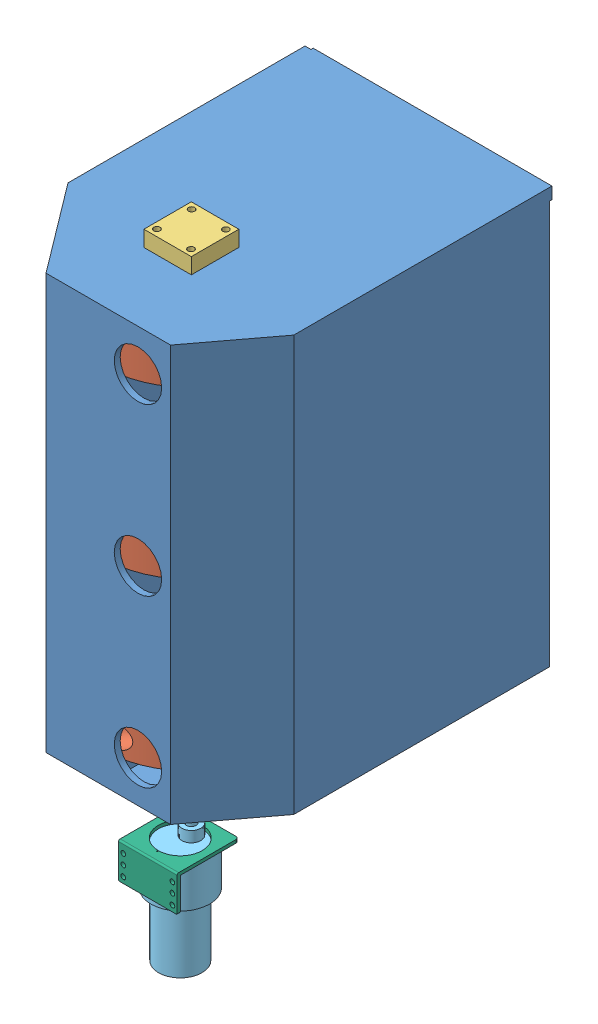
SolidWorks assembly seed drill tank, configuration Default. Lengths in mm.
Overall size (158.83 396.8 236.15).
9 component instances, 7 part files, 22 mates.
Components (placement in the parent):
- container-1: container [Default] at (54.6406 23.9076 482.5633) size (154.72 292.5 217.66)
- divider-1: divider [Default] at (46.3176 108.9519 394.803) x (-0.517121 0 0.855912) z (0.855912 0 0.517121) size (111 22.5 111)
- divider-2: divider [Default] at (46.3176 318.9519 394.803) x (0.703833 0 0.710366) z (0.710366 0 -0.703833) size (111 22.5 111)
- divider-3: divider [Default] at (46.3176 213.9519 394.803) x (0.414054 0 0.910252) z (0.910252 0 -0.414054) size (111 22.5 111)
- ball bearing-1: ball bearing [Default] at (46.3176 340.2019 394.803) x (0 0 -1) z (-1 0 0) size (30 10 30)
- bearing-1: bearing [Default] at (46.3176 67.7019 394.803) x (-1 0 0) z (0 0 1) size (30.31 10 30)
- DC motor-1: DC motor [Default] at (46.3176 8.4019 401.803) x (-1 0 0) z (0 -1 0) size (37 37 101.8)
- DCclamp-1: DCclamp [Default] at (27.8176 8.4019 420.303) x (0 -1 0) z (1 0 0) size (22.5 39 37)
- shaft-1: shaft [Default] at (46.3176 52.2019 394.803) x (0 0 1) z (1 0 0) size (16.38 20 16.38)
Mates (geometry in assembly coordinates):
- Coincident2: coincident: plane of container-1 through (42.5676 315.2019 451.053) normal (0 -1 0); plane of divider-2 through (46.3176 315.2019 394.803) normal (0 1 0)
- Coincident3: coincident: plane of container-1 through (42.5676 187.7019 451.053) normal (0 1 0); plane of divider-3 through (46.3176 187.7019 394.803) normal (0 -1 0)
- Coincident4: coincident: plane of container-1 through (42.5676 105.2019 451.053) normal (0 -1 0); plane of divider-1 through (46.3176 105.2019 394.803) normal (0 1 0)
- Concentric4: concentric: cylinder of container-1 through (46.3176 337.7019 394.803) axis (0 -1 0) radius 3; cylinder of divider-3 through (46.3176 210.2019 394.803) axis (0 -1 0) radius 2.25
- Concentric5: concentric: cylinder of container-1 through (46.3176 337.7019 394.803) axis (0 -1 0) radius 3; cylinder of divider-1 through (46.3176 105.2019 394.803) axis (0 -1 0) radius 2.25
- Concentric6: concentric: cylinder of container-1 through (46.3176 337.7019 394.803) axis (0 -1 0) radius 3; cylinder of divider-2 through (46.3176 315.2019 394.803) axis (0 -1 0) radius 2.25
- Concentric7: concentric: cylinder of container-1 through (46.3176 337.7019 394.803) axis (0 -1 0) radius 3; cylinder of ball bearing-1 through (46.3176 337.2019 394.803) axis (0 -1 0) radius 4
- Coincident5: coincident: plane of container-1 through (53.8176 330.2019 451.053) normal (0 1 0); plane of ball bearing-1 through (46.3176 330.2019 394.803) normal (0 -1 0)
- Parallel1: parallel: plane of container-1 through (-24.3049 322.7019 247.1451) normal (0 0 -1); plane of ball bearing-1 through (61.3176 330.2019 379.803) normal (0 0 -1)
- Concentric8: concentric: cylinder of container-1 through (46.3176 337.7019 394.803) axis (0 -1 0) radius 3; cylinder of bearing-1 through (46.3176 67.7019 394.803) axis (0 -1 0) radius 4
- Parallel2: parallel: plane of container-1 through (-28.0549 330.2019 248.553) normal (0 0 -1); plane of bearing-1 through (61.4713 57.7019 379.8017) normal (0 0 -1)
- Coincident8: coincident: plane of container-1 through (53.8176 67.7019 451.053) normal (0 -1 0); plane of bearing-1 through (46.3176 67.7019 394.803) normal (0 1 0)
- Concentric9: concentric: cylinder of container-1 through (46.3176 337.7019 394.803) axis (0 -1 0) radius 3; cylinder of ? through (46.3176 1.2019 394.803) axis (0 1 0) radius 4
- Coincident9: coincident: plane of container-1 through (46.3176 45.2019 394.803) normal (0 -1 0); plane of ? through (46.3176 45.2019 394.803) normal (0 1 0)
- Concentric10: concentric: cylinder of container-1 through (46.3176 337.7019 394.803) axis (0 -1 0) radius 3; cylinder of DC motor-1 through (46.3176 45.2019 394.803) axis (0 -1 0) radius 3
- Coincident10: coincident: plane of container-1 through (46.3176 45.2019 394.803) normal (0 -1 0); circle of DC motor-1
- Concentric12: concentric: cylinder of DC motor-1 through (46.3176 -16.5981 401.803) axis (0 1 0) radius 18.5; cylinder of DCclamp-1 through (46.3176 18.4019 401.803) axis (0 -1 0) radius 13.8601
- Coincident11: coincident: plane of DC motor-1 through (46.3176 8.4019 401.803) normal (0 1 0); plane of DCclamp-1 through (64.8176 8.4019 420.303) normal (0 -1 0)
- Parallel3: parallel: plane of container-1 through (16.3176 330.2019 454.803) normal (0 0 1); plane of DCclamp-1 through (64.8176 9.4019 422.303) normal (0 0 1)
- Concentric13: concentric: cylinder of DC motor-1 through (46.3176 37.2019 402.303) axis (0 0 -1) radius 1.3505; cylinder of shaft-1 through (46.3176 37.2019 404.803) axis (0 0 -1) radius 1.5
- Concentric14: concentric: cylinder of container-1 through (46.3176 337.7019 394.803) axis (0 -1 0) radius 3; cylinder of shaft-1 through (46.3176 32.2019 394.803) axis (0 1 0) radius 8.189
- Parallel4: parallel: plane of container-1 through (-28.0549 330.2019 248.553) normal (0 0 -1); plane of DC motor-1 through (46.3176 33.2019 392.303) normal (0 0 -1)
